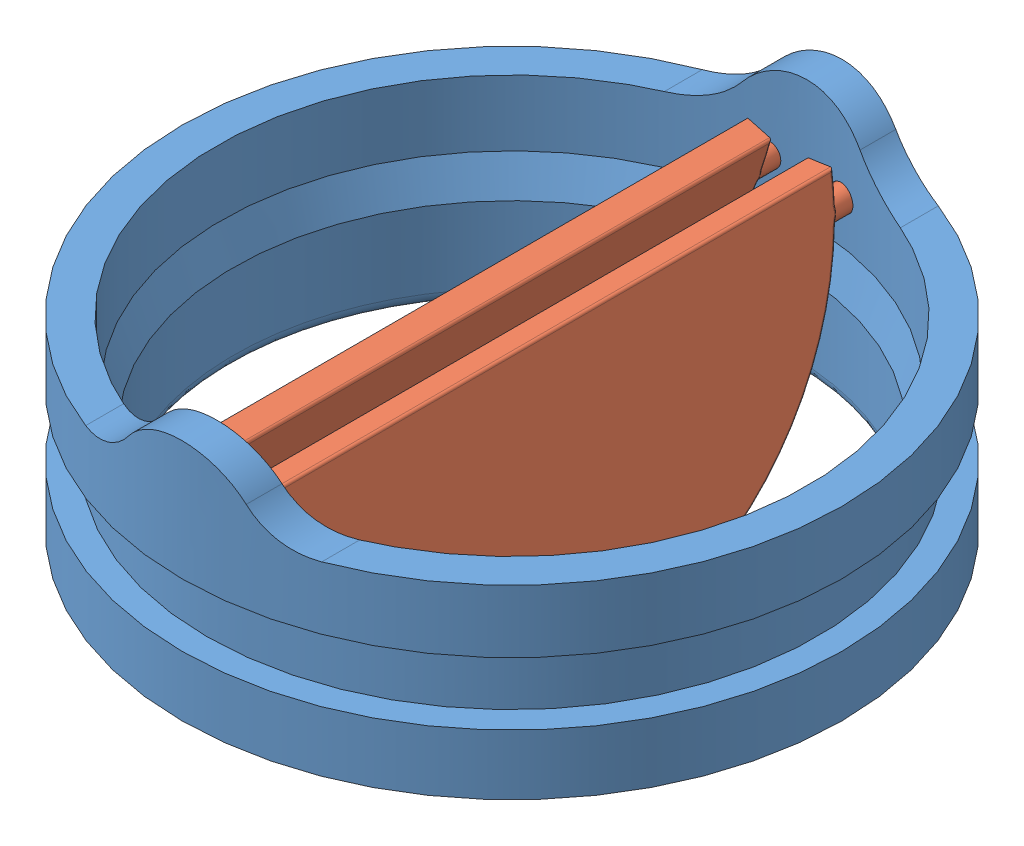
SolidWorks assembly Assem1, configuration Default. Lengths in mm.
Overall size (26.3 12.8 26.3).
3 component instances, 2 part files, 4 mates.
Components (placement in the parent):
- mechanical heart valve-1: mechanical heart valve [Default] at (-4.4313 10.6501 29.0235) size (26.3 9.67 26.3)
- Part1-1: Part1 [Default] at (-2.0215 3.8206 29.0235) x (0 0 1) z (0.989224 0.146412 0) size (25 11.01 1.01)
- Part1-2: Part1 [Default] at (-8.9013 4.2497 29.0235) x (0 0 1) z (0.96543 -0.260662 0) size (25 11.01 1.01)
Mates (geometry in assembly coordinates):
- Concentric1: concentric: cylinder of assembly; cylinder of assembly; cylinder of mechanical heart valve-1 through (-2.9313 13.3501 16.5235) axis (0 0 1) radius 0.5; cylinder of Part1-1 through (-2.9313 13.3501 41.5235) axis (0 0 -1) radius 0.495
- Coincident1: coincident: plane of assembly; plane of assembly; plane of mechanical heart valve-1 through (-2.9313 13.3501 16.5235) normal (0 0 1); plane of Part1-1 through (-2.9313 13.3501 16.5235) normal (0 0 -1)
- Concentric2: concentric: cylinder of assembly; cylinder of assembly; cylinder of mechanical heart valve-1 through (-5.9313 13.3501 16.5235) axis (0 0 1) radius 0.5; cylinder of Part1-2 through (-5.9313 13.3501 41.5235) axis (0 0 -1) radius 0.495
- Coincident2: coincident: plane of assembly; plane of assembly; plane of mechanical heart valve-1 through (-5.9313 13.3501 16.5235) normal (0 0 1); plane of Part1-2 through (-5.9313 13.3501 16.5235) normal (0 0 -1)
